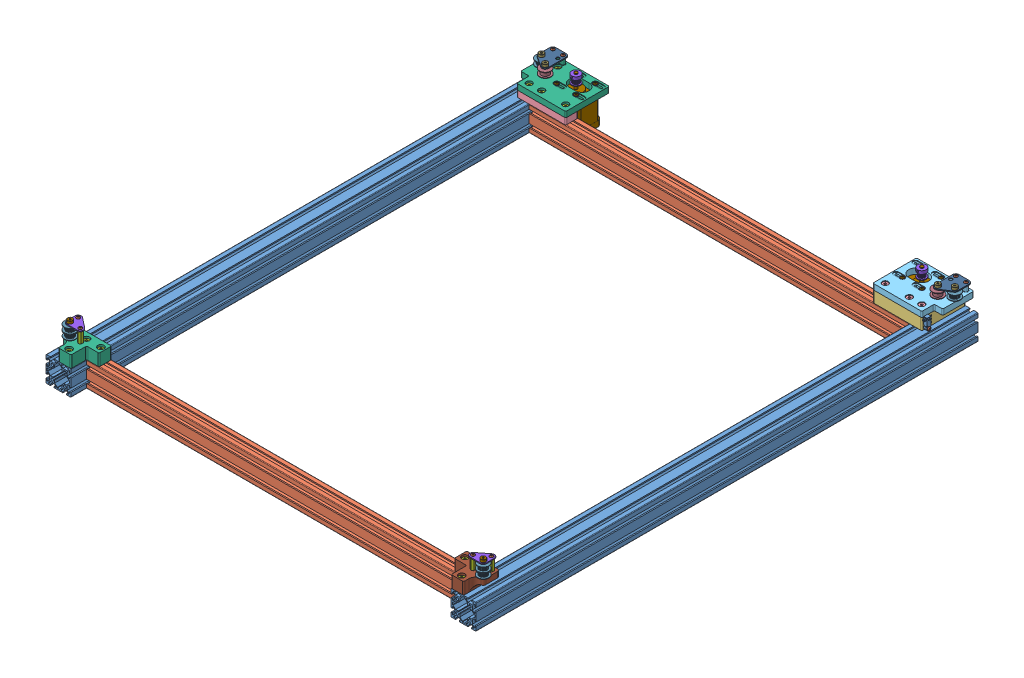
SolidWorks assembly BigCoreXYFrame, configuration Default. Lengths in mm.
Overall size (689 83.14 804).
125 component instances, 29 part files, 15 mates.
Components (placement in the parent):
- BaseModel20200203215901-4: BaseModel20200203215901 [Default] at (0 0.4187 49.2065) x (0 0 -1) z (0 -1 0) size (804 40 40)
- BaseModel20200203215901-3: BaseModel20200203215901 [Default] at (649 0.4187 49.2065) x (0 0 -1) z (0 -1 0) size (804 40 40)
- MISUMI_NFS5-2040-609.0-1: MISUMI_NFS5-2040-609.0 [Default] at (20 0.4187 -694.7935) size (609 40 20)
- MISUMI_NFS5-2040-609.0-2: MISUMI_NFS5-2040-609.0 [Default] at (20 0.4187 14.2065) size (609 40 20)
- left_motor_plate_assembly-1: left_motor_plate_assembly [Default] at (74.929 -353.5918 -700.1092) size (94 73.14 70)
  - m5_locking_t_nut_20x20_generic-1: m5_locking_t_nut_20x20_generic [Default] at (-9.429 368.8105 5.3157) x (0 0 -1) z (1 0 0) size (10 4.5 6)
  - m5_locking_t_nut_20x20_generic-2: m5_locking_t_nut_20x20_generic [Default] at (-64.929 368.8105 2.3157) size (10 4.5 6)
  - m5_locking_t_nut_20x20_generic-3: m5_locking_t_nut_20x20_generic [Default] at (-64.929 368.8105 -43.6843) size (10 4.5 6)
  - m5_locking_t_nut_20x20_generic-4: m5_locking_t_nut_20x20_generic [Default] at (-47.929 368.8105 5.3157) x (0 0 -1) z (1 0 0) size (10 4.5 6)
  - short_motor_corner_plate_spacer_with_insert-1: short_motor_corner_plate_spacer_with_insert [Default] at (-74.929 374.0105 -59.4612) x (0 0 -1) z (0 -1 0) size (70 78.5 10)
    - motor_corner_bracket_spacer_Left Motor Corner Bracket Spacer-1: motor_corner_bracket_spacer_Left Motor Corner Bracket Spacer [Default] at (-74.7769 0 0) x (0 1 0) z (-1 0 0) size (78.5 10 70)
    - m4_heat_set_insert_long_94180A353_94180A353-1: m4_heat_set_insert_long_94180A353_94180A353 [Default] at (-27.2769 20 -5.5) x (0.97178 0 0.235889) z (-0.235889 0 0.97178) size (6.35 8 6.35)
  - left_motor_plate_with_inserts-1: left_motor_plate_with_inserts [Default] at origin size (92 19 70)
    - m4_heat_set_insert_long_94180A353_94180A353-1: m4_heat_set_insert_long_94180A353_94180A353 [Default] at (-81.429 393.0105 -31.0093) size (6.35 8 6.35)
    - motor_corner_bracket_Left Motor Corner Bracket-1: motor_corner_bracket_Left Motor Corner Bracket [Default] at (-74.929 384.0105 15.3157) size (92 19 70)
    - m4_heat_set_insert_long_94180A353_94180A353-2: m4_heat_set_insert_long_94180A353_94180A353 [Default] at (-64.929 393.0105 -20.3843) size (6.35 8 6.35)
  - m5_low_profile_screw_template_M5 x 20-1: m5_low_profile_screw_template_M5 x 20 [Default] at (-44.929 368.8105 5.3157) x (0 -1 0) z (-0.441015 0 -0.8975) size (21.62 9 9)
  - m5_low_profile_screw_template_M5 x 20-2: m5_low_profile_screw_template_M5 x 20 [Default] at (-64.929 368.8105 5.3157) x (0 -1 0) z (0.595693 0 0.803212) size (21.62 9 9)
  - m5_low_profile_screw_template_M5 x 20-3: m5_low_profile_screw_template_M5 x 20 [Default] at (-64.929 368.8105 -40.6843) x (0 -1 0) z (0.317209 0 -0.948356) size (21.62 9 9)
  - m5_low_profile_screw_template_M5 x 20-4: m5_low_profile_screw_template_M5 x 20 [Default] at (-6.429 368.8105 5.3157) x (0 -1 0) z (-0.441015 0 -0.8975) size (21.62 9 9)
  - xy_drive_stepper-1: xy_drive_stepper [Default] at origin size (42.42 72 42.42)
    - drive_pulley_16t_gt2_6mm_belt-1: drive_pulley_16t_gt2_6mm_belt [Default] at (-27.429 406.7309 -32.1843) x (-0.044306 0 -0.999018) z (-0.999018 0 0.044306) size (13.8 13.5 13.8)
    - 17HM19-2004S-1: 17HM19-2004S [Default] at (-27.429 384.0105 -32.1843) x (-1 0 0) z (0 1 0) size (42.42 42.42 72)
  - motor_plate_reinforcement-1: motor_plate_reinforcement [Default] at (-86.429 403.0105 -54.0093) size (26.5 1.57 38.62)
  - m3_6mm_buttonhead_screw_92095A179_92095A179-1: m3_6mm_buttonhead_screw_92095A179_92095A179 [Default] at (-81.429 406.2305 -49.0093) x (1 0 0) z (0 1 0) size (5.74 5.77 8.05)
  - m3_6mm_buttonhead_screw_92095A179_92095A179-2: m3_6mm_buttonhead_screw_92095A179_92095A179 [Default] at (-64.929 406.2305 -49.0093) x (1 0 0) z (0 1 0) size (5.74 5.77 8.05)
  - m4_shoulder_screw_5mm_d_12mm_l_90278A371_90278A371-1: m4_shoulder_screw_5mm_d_12mm_l_90278A371_90278A371 [Default] at (-64.929 409.0105 -20.3843) x (1 0 0) z (0 1 0) size (8 8 21.19)
  - m4_shoulder_screw_5mm_d_12mm_l_90278A371_90278A371-2: m4_shoulder_screw_5mm_d_12mm_l_90278A371_90278A371 [Default] at (-81.429 409.0105 -31.0093) x (1 0 0) z (0 1 0) size (8 8 21.19)
  - 20t_toothless_idler_5mm_bore-1: 20t_toothless_idler_5mm_bore [Default] at (-64.929 393.2105 -20.3843) x (0.999784 0 0.020777) z (-0.020777 0 0.999784) size (18 8.5 18)
  - 20t_idler_5mm_bore-1: 20t_idler_5mm_bore [Default] at (-81.429 393.2105 -31.0093) size (18 8.5 18)
  - m5_shim_0.2mm_thick_98089A246_98089A246-1: m5_shim_0.2mm_thick_98089A246_98089A246 [Default] at (-64.929 393.2105 -20.3843) x (-0.674811 0 -0.73799) z (-0.73799 0 0.674811) size (10 0.2 10)
  - m5_shim_0.2mm_thick_98089A246_98089A246-2: m5_shim_0.2mm_thick_98089A246_98089A246 [Default] at (-81.429 393.2105 -31.0093) x (-0.777784 0 -0.628532) z (-0.628532 0 0.777784) size (10 0.2 10)
  - m4_set_screw_25mm_92605A124_92605A124-1: m4_set_screw_25mm_92605A124_92605A124 [Default] at (-64.429 379.5105 -32.1843) x (0 0.718145 0.695894) z (-1 0 0) size (4.05 4.11 25.09)
  - m3_stainless_steel_washer_90965A130_90965A130-1: m3_stainless_steel_washer_90965A130_90965A130 [Default] at (-42.929 391.8105 -47.6843) x (1 0 0) z (0 1 0) size (7 7 0.6)
  - m3_12mm_buttohead_screw_92095A183_92095A183-1: m3_12mm_buttohead_screw_92095A183_92095A183 [Default] at (-42.929 394.0605 -47.6843) x (1 0 0) z (0 1 0) size (5.74 5.77 14.06)
  - m3_12mm_buttohead_screw_92095A183_92095A183-2: m3_12mm_buttohead_screw_92095A183_92095A183 [Default] at (-11.929 394.0605 -47.6843) x (0 0 1) z (0 1 0) size (5.74 5.77 14.06)
  - m3_12mm_buttohead_screw_92095A183_92095A183-3: m3_12mm_buttohead_screw_92095A183_92095A183 [Default] at (-11.929 394.0605 -16.6843) x (-1 0 0) z (0 1 0) size (5.74 5.77 14.06)
  - m3_12mm_buttohead_screw_92095A183_92095A183-4: m3_12mm_buttohead_screw_92095A183_92095A183 [Default] at (-42.929 394.0605 -16.6843) x (0 0 -1) z (0 1 0) size (5.74 5.77 14.06)
  - m3_stainless_steel_washer_90965A130_90965A130-2: m3_stainless_steel_washer_90965A130_90965A130 [Default] at (-11.929 391.8105 -47.6843) x (0 0 1) z (0 1 0) size (7 7 0.6)
  - m3_stainless_steel_washer_90965A130_90965A130-3: m3_stainless_steel_washer_90965A130_90965A130 [Default] at (-11.929 391.8105 -16.6843) x (-1 0 0) z (0 1 0) size (7 7 0.6)
  - m3_stainless_steel_washer_90965A130_90965A130-4: m3_stainless_steel_washer_90965A130_90965A130 [Default] at (-42.929 391.8105 -16.6843) x (0 0 -1) z (0 1 0) size (7 7 0.6)
- right_motor_plate_assembly-1: right_motor_plate_assembly [Default] at (294.929 -353.5918 -700.1092) size (94 73.14 71.2)
  - tall_motor_corner_plate_spacer_assembly-1: tall_motor_corner_plate_spacer_assembly [Default] at origin size (85.83 18.61 71.2)
    - D2HW_C201H-1: D2HW_C201H [Default] at (354.071 389.8605 9.3157) x (0 -1 0) z (-1 0 0) size (18.5 14.2 8.3)
    - m3_8mm_buttonhead_screw_92095A181_92095A181-1: m3_8mm_buttonhead_screw_92095A181_92095A181 [Default] at (361.021 376.8605 9.3157) x (0 -0.028648 -0.99959) z (1 0 0) size (5.74 5.77 10.05)
    - tall_motor_corner_plate_spacer_with_insert-1: tall_motor_corner_plate_spacer_with_insert [Default] at (354.071 392.0105 -198.139) x (0 0 -1) z (0 1 0) size (70 78.5 18)
      - motor_corner_bracket_spacer_Right Motor Corner Bracket Spacer-1: motor_corner_bracket_spacer_Right Motor Corner Bracket Spacer [Default] at (-213.4548 157 -10) x (0 -1 0) z (-1 0 0) size (78.5 18 70)
      - m4_heat_set_insert_long_94180A353_94180A353-1: m4_heat_set_insert_long_94180A353_94180A353 [Default] at (-165.9548 20 -4.5) x (0.989318 0 -0.145772) z (0.145772 0 0.989318) size (6.35 8 6.35)
    - m4_set_screw_25mm_92605A124_92605A124-1: m4_set_screw_25mm_92605A124_92605A124 [Default] at (345.571 387.5105 -32.1843) x (0 -0.291374 0.956609) z (1 0 0) size (4.05 4.11 25.09)
  - m5_low_profile_screw_template_M5 x 30-1: m5_low_profile_screw_template_M5 x 30 [Default] at (344.071 368.8105 5.3157) x (0 -1 0) z (-0.571239 0 -0.820784) size (31.62 9 9)
  - m5_low_profile_screw_template_M5 x 30-2: m5_low_profile_screw_template_M5 x 30 [Default] at (324.071 368.8105 5.3157) x (0 -1 0) z (-0.571239 0 -0.820784) size (31.62 9 9)
  - m5_low_profile_screw_template_M5 x 30-3: m5_low_profile_screw_template_M5 x 30 [Default] at (285.571 368.8105 5.3157) x (0 -1 0) z (-0.917889 0 0.396837) size (31.62 9 9)
  - motor_plate_reinforcement-1: motor_plate_reinforcement [Default] at (365.699 412.5805 -53.9811) x (-0.999984 0 -0.005572) z (-0.005572 0 0.999984) size (26.5 1.57 38.62)
  - m3_6mm_buttonhead_screw_92095A179_92095A179-1: m3_6mm_buttonhead_screw_92095A179_92095A179 [Default] at (344.1715 414.2305 -49.1009) x (1 0 0) z (0 1 0) size (5.74 5.77 8.05)
  - m3_6mm_buttonhead_screw_92095A179_92095A179-2: m3_6mm_buttonhead_screw_92095A179_92095A179 [Default] at (360.6712 414.2305 -49.009) x (1 0 0) z (0 1 0) size (5.74 5.77 8.05)
  - m4_shoulder_screw_5mm_d_12mm_l_90278A371_90278A371-1: m4_shoulder_screw_5mm_d_12mm_l_90278A371_90278A371 [Default] at (360.571 417.0105 -31.0093) x (1 0 0) z (0 1 0) size (8 8 21.19)
  - m4_shoulder_screw_5mm_d_12mm_l_90278A371_90278A371-2: m4_shoulder_screw_5mm_d_12mm_l_90278A371_90278A371 [Default] at (344.071 417.0105 -20.3843) x (1 0 0) z (0 1 0) size (8 8 21.19)
  - m3_12mm_buttohead_screw_92095A183_92095A183-1: m3_12mm_buttohead_screw_92095A183_92095A183 [Default] at (291.071 402.0605 -47.6843) x (1 0 0) z (0 1 0) size (5.74 5.77 14.06)
  - m3_stainless_steel_washer_90965A130_90965A130-1: m3_stainless_steel_washer_90965A130_90965A130 [Default] at (291.071 399.8105 -47.6843) x (0.988493 0 -0.151268) z (0 1 0) size (7 7 0.6)
  - xy_drive_stepper_2-1: xy_drive_stepper_2 [Default] at (334 8 0) size (42.42 72 42.42)
    - drive_pulley_16t_gt2_6mm_belt-1: drive_pulley_16t_gt2_6mm_belt [Default] at (-27.429 406.7309 -32.1843) x (-0.044306 0 -0.999018) z (-0.999018 0 0.044306) size (13.8 13.5 13.8)
    - 17HM19-2004S-1: 17HM19-2004S [Default] at (-27.429 384.0105 -32.1843) x (-1 0 0) z (0 1 0) size (42.42 42.42 72)
  - m5_locking_t_nut_20x20_generic-1: m5_locking_t_nut_20x20_generic [Default] at (344.071 368.8105 -37.6843) x (-1 0 0) z (0 0 -1) size (10 4.5 6)
  - m5_locking_t_nut_20x20_generic-2: m5_locking_t_nut_20x20_generic [Default] at (344.071 368.8105 8.3157) x (-1 0 0) z (0 0 -1) size (10 4.5 6)
  - m5_locking_t_nut_20x20_generic-3: m5_locking_t_nut_20x20_generic [Default] at (288.571 368.8105 5.3157) x (0 0 1) z (-1 0 0) size (10 4.5 6)
  - m5_locking_t_nut_20x20_generic-4: m5_locking_t_nut_20x20_generic [Default] at (327.071 368.8105 5.3157) x (0 0 1) z (-1 0 0) size (10 4.5 6)
  - m5_shim_0.2mm_thick_98089A246_98089A246-1: m5_shim_0.2mm_thick_98089A246_98089A246 [Default] at (360.571 401.2105 -31.0093) x (0.674811 0 0.73799) z (0.73799 0 -0.674811) size (10 0.2 10)
  - m5_shim_0.2mm_thick_98089A246_98089A246-2: m5_shim_0.2mm_thick_98089A246_98089A246 [Default] at (344.071 401.0105 -20.3843) x (-0.968571 0 0.248739) z (-0.248739 0 -0.968571) size (10 0.2 10)
  - right_motor_plate_with_inserts-1: right_motor_plate_with_inserts [Default] at origin size (92 19 70)
    - motor_corner_bracket_Right Motor Corner Bracket-1: motor_corner_bracket_Right Motor Corner Bracket [Default] at (197.071 392.0105 15.3157) size (92 19 70)
    - m4_heat_set_insert_long_94180A353_94180A353-1: m4_heat_set_insert_long_94180A353_94180A353 [Default] at (360.571 401.0105 -31.0093) size (6.35 8 6.35)
    - m4_heat_set_insert_long_94180A353_94180A353-2: m4_heat_set_insert_long_94180A353_94180A353 [Default] at (344.071 401.0105 -20.3843) size (6.35 8 6.35)
  - m5_low_profile_screw_template_M5 x 30-4: m5_low_profile_screw_template_M5 x 30 [Default] at (344.071 368.8105 -40.6843) x (0 -1 0) z (-0.6826 0 -0.730792) size (31.62 9 9)
  - 20t_toothless_idler_5mm_bore-1: 20t_toothless_idler_5mm_bore [Default] at (344.071 401.2105 -20.3843) x (0.998302 0 -0.058244) z (0.058244 0 0.998302) size (18 8.5 18)
  - 20t_idler_5mm_bore-1: 20t_idler_5mm_bore [Default] at (360.571 401.2105 -31.0093) size (18 8.5 18)
  - m3_stainless_steel_washer_90965A130_90965A130-2: m3_stainless_steel_washer_90965A130_90965A130 [Default] at (322.071 399.8105 -47.6843) x (0.151268 0 0.988493) z (0 1 0) size (7 7 0.6)
  - m3_stainless_steel_washer_90965A130_90965A130-3: m3_stainless_steel_washer_90965A130_90965A130 [Default] at (322.071 399.8105 -16.6843) x (-0.988493 0 0.151268) z (0 1 0) size (7 7 0.6)
  - m3_stainless_steel_washer_90965A130_90965A130-4: m3_stainless_steel_washer_90965A130_90965A130 [Default] at (291.071 399.8105 -16.6843) x (-0.151268 0 -0.988493) z (0 1 0) size (7 7 0.6)
  - m3_12mm_buttohead_screw_92095A183_92095A183-2: m3_12mm_buttohead_screw_92095A183_92095A183 [Default] at (322.071 402.0605 -47.6843) x (0 0 1) z (0 1 0) size (5.74 5.77 14.06)
  - m3_12mm_buttohead_screw_92095A183_92095A183-3: m3_12mm_buttohead_screw_92095A183_92095A183 [Default] at (322.071 402.0605 -16.6843) x (-1 0 0) z (0 1 0) size (5.74 5.77 14.06)
  - m3_12mm_buttohead_screw_92095A183_92095A183-4: m3_12mm_buttohead_screw_92095A183_92095A183 [Default] at (291.071 402.0605 -16.6843) x (0 0 -1) z (0 1 0) size (5.74 5.77 14.06)
- left_corner_pulley_assembly-1: left_corner_pulley_assembly [Default] at (74.929 -353.5918 -479.1092) size (55.52 48.14 55)
  - left_corner_plate_with_insert-1: left_corner_plate_with_insert [Default] at origin size (53 19.06 55)
    - double_pulley_corner_bracket_Left Double Pulley Corner Bracket-1: double_pulley_corner_bracket_Left Double Pulley Corner Bracket [Default] at (-74.929 374.0105 528.3157) size (53 19.01 55)
    - m4_heat_set_insert_long_94180A353_94180A353-1: m4_heat_set_insert_long_94180A353_94180A353 [Default] at (-81.429 393.0105 503.3157) size (6.35 8 6.35)
  - m3_18mm_hex_standoff_6mm_wide_95947A525_95947A525-1: m3_18mm_hex_standoff_6mm_wide_95947A525_95947A525 [Default] at (-81.429 402.0105 490.3157) x (1 0 0) z (0 1 0) size (6 6.93 18)
  - m3_18mm_hex_standoff_6mm_wide_95947A525_95947A525-2: m3_18mm_hex_standoff_6mm_wide_95947A525_95947A525 [Default] at (-64.929 402.0105 503.3157) x (1 0 0) z (0 1 0) size (6 6.93 18)
  - back_pulley_reinforcement_plate-1: back_pulley_reinforcement_plate [Default] at (-81.429 411.0105 503.3157) size (26.5 1.57 23)
  - m4_shoulder_screw_5mm_d_20mm_l_90278A374_90278A374-1: m4_shoulder_screw_5mm_d_20mm_l_90278A374_90278A374 [Default] at (-81.429 417.0105 503.3157) x (0.147585 0 0.989049) z (0 1 0) size (8 8 29.19)
  - m3_6mm_buttonhead_screw_92095A179_92095A179-1: m3_6mm_buttonhead_screw_92095A179_92095A179 [Default] at (-81.429 414.2305 490.3157) x (1 0 0) z (0 1 0) size (5.74 5.77 8.05)
  - m3_6mm_buttonhead_screw_92095A179_92095A179-2: m3_6mm_buttonhead_screw_92095A179_92095A179 [Default] at (-64.929 414.2305 503.3157) x (1 0 0) z (0 1 0) size (5.74 5.77 8.05)
  - m3_10mm_buttonhead_screw_92095A182_92095A182-1: m3_10mm_buttonhead_screw_92095A182_92095A182 [Default] at (-81.429 385.3605 490.3157) x (1 0 0) z (0 -1 0) size (5.74 5.77 12.06)
  - m3_10mm_buttonhead_screw_92095A182_92095A182-2: m3_10mm_buttonhead_screw_92095A182_92095A182 [Default] at (-64.929 385.3605 503.3157) x (1 0 0) z (0 -1 0) size (5.74 5.77 12.06)
  - m5_low_profile_screw_template_M5 x 20-1: m5_low_profile_screw_template_M5 x 20 [Default] at (-64.929 369.0105 521.3157) x (0 -1 0) z (-0.953053 0 -0.302804) size (21.62 9 9)
  - m5_low_profile_screw_template_M5 x 20-2: m5_low_profile_screw_template_M5 x 20 [Default] at (-64.929 369.0105 493.3157) x (0 -1 0) z (0.203237 0 -0.979129) size (21.62 9 9)
  - m5_low_profile_screw_template_M5 x 20-3: m5_low_profile_screw_template_M5 x 20 [Default] at (-41.929 369.0105 493.3157) x (0 -1 0) z (0.194951 0 -0.980813) size (21.62 9 9)
  - m5_shim_0.2mm_thick_98089A246_98089A246-1: m5_shim_0.2mm_thick_98089A246_98089A246 [Default] at (-81.429 393.0105 503.3157) size (10 0.2 10)
  - 20t_idler_5mm_bore-1: 20t_idler_5mm_bore [Default] at (-81.429 393.2105 503.3157) x (0.999997 0 0.002498) z (-0.002498 0 0.999997) size (18 8.5 18)
  - m5_shim_0.2mm_thick_98089A246_98089A246-2: m5_shim_0.2mm_thick_98089A246_98089A246 [Default] at (-81.429 401.7105 503.3157) size (10 0.2 10)
  - 20t_idler_5mm_bore-2: 20t_idler_5mm_bore [Default] at (-81.429 401.9105 503.3157) x (0.999997 0 0.002498) z (-0.002498 0 0.999997) size (18 8.5 18)
  - m5_locking_t_nut_20x20_generic-1: m5_locking_t_nut_20x20_generic [Default] at (-64.929 369.0105 518.3157) size (10 4.5 6)
  - m5_locking_t_nut_20x20_generic-2: m5_locking_t_nut_20x20_generic [Default] at (-64.929 369.0105 490.3157) size (10 4.5 6)
  - m5_locking_t_nut_20x20_generic-3: m5_locking_t_nut_20x20_generic [Default] at (-44.929 369.0105 493.3157) x (0 0 -1) z (1 0 0) size (10 4.5 6)
- right_corner_pulley_assembly-1: right_corner_pulley_assembly [Default] at (294.929 -353.5918 -479.1092) size (58.84 48.14 55)
  - right_corner_plate_with_insert-1: right_corner_plate_with_insert [Default] at (10 0 0) size (53 19.05 55)
    - double_pulley_corner_bracket_Right Double Pulley Corner Bracket-1: double_pulley_corner_bracket_Right Double Pulley Corner Bracket [Default] at (264.071 374.0105 528.3157) size (53 19 55)
    - m4_heat_set_insert_long_94180A353_94180A353-1: m4_heat_set_insert_long_94180A353_94180A353 [Default] at (350.571 393.0105 503.3157) size (6.35 8 6.35)
  - m3_18mm_hex_standoff_6mm_wide_95947A525_95947A525-1: m3_18mm_hex_standoff_6mm_wide_95947A525_95947A525 [Default] at (360.571 402.0105 490.3157) x (1 0 0) z (0 1 0) size (6 6.93 18)
  - m3_18mm_hex_standoff_6mm_wide_95947A525_95947A525-2: m3_18mm_hex_standoff_6mm_wide_95947A525_95947A525 [Default] at (344.071 402.0105 503.3157) x (1 0 0) z (0 1 0) size (6 6.93 18)
  - back_pulley_reinforcement_plate-1: back_pulley_reinforcement_plate [Default] at (360.571 412.5805 503.3157) x (-1 0 0) z (0 0 1) size (26.5 1.57 23)
  - m4_shoulder_screw_5mm_d_20mm_l_90278A374_90278A374-1: m4_shoulder_screw_5mm_d_20mm_l_90278A374_90278A374 [Default] at (360.571 417.0105 503.3157) x (0.147585 0 0.989049) z (0 1 0) size (8 8 29.19)
  - m3_10mm_buttonhead_screw_92095A182_92095A182-1: m3_10mm_buttonhead_screw_92095A182_92095A182 [Default] at (344.071 385.3605 503.3157) x (1 0 0) z (0 -1 0) size (5.74 5.77 12.06)
  - m3_10mm_buttonhead_screw_92095A182_92095A182-2: m3_10mm_buttonhead_screw_92095A182_92095A182 [Default] at (360.571 385.3605 490.3157) x (1 0 0) z (0 -1 0) size (5.74 5.77 12.06)
  - m3_6mm_buttonhead_screw_92095A179_92095A179-1: m3_6mm_buttonhead_screw_92095A179_92095A179 [Default] at (360.571 414.2305 490.3157) x (1 0 0) z (0 1 0) size (5.74 5.77 8.05)
  - m3_6mm_buttonhead_screw_92095A179_92095A179-2: m3_6mm_buttonhead_screw_92095A179_92095A179 [Default] at (344.071 414.2305 503.3157) x (1 0 0) z (0 1 0) size (5.74 5.77 8.05)
  - m5_low_profile_screw_template_M5 x 20-1: m5_low_profile_screw_template_M5 x 20 [Default] at (321.071 369.0105 493.3157) x (0 -1 0) z (0.874861 0 0.484375) size (21.62 9 9)
  - m5_low_profile_screw_template_M5 x 20-2: m5_low_profile_screw_template_M5 x 20 [Default] at (344.071 369.0105 493.3157) x (0 -1 0) z (0.874267 0 0.485445) size (21.62 9 9)
  - m5_low_profile_screw_template_M5 x 20-3: m5_low_profile_screw_template_M5 x 20 [Default] at (344.071 369.0105 521.3157) x (0 -1 0) z (-0.681019 0 0.732266) size (21.62 9 9)
  - 20t_idler_5mm_bore-1: 20t_idler_5mm_bore [Default] at (360.571 393.2105 503.3157) x (0.999997 0 0.002498) z (-0.002498 0 0.999997) size (18 8.5 18)
  - 20t_idler_5mm_bore-2: 20t_idler_5mm_bore [Default] at (360.571 401.9105 503.3157) x (0.85881 0 0.512295) z (-0.512295 0 0.85881) size (18 8.5 18)
  - m5_locking_t_nut_20x20_generic-1: m5_locking_t_nut_20x20_generic [Default] at (344.071 369.0105 518.3157) size (10 4.5 6)
  - m5_locking_t_nut_20x20_generic-2: m5_locking_t_nut_20x20_generic [Default] at (344.071 369.0105 490.3157) size (10 4.5 6)
  - m5_locking_t_nut_20x20_generic-3: m5_locking_t_nut_20x20_generic [Default] at (318.071 369.0105 493.3157) x (0 0 -1) z (1 0 0) size (10 4.5 6)
  - m5_shim_0.2mm_thick_98089A246_98089A246-1: m5_shim_0.2mm_thick_98089A246_98089A246 [Default] at (360.571 393.0105 503.3157) x (0.760721 0 -0.649079) z (0.649079 0 0.760721) size (10 0.2 10)
  - m5_shim_0.2mm_thick_98089A246_98089A246-2: m5_shim_0.2mm_thick_98089A246_98089A246 [Default] at (360.571 401.7105 503.3157) x (0.760721 0 -0.649079) z (0.649079 0 0.760721) size (10 0.2 10)
Mates (geometry in assembly coordinates):
- Coincident29: coincident anti-aligned: plane of BaseModel20200203215901-3 through (629 -6.5813 -754.7935) normal (-1 0 0); plane of MISUMI_NFS5-2040-609.0-1 through (629 -18.5813 -685.7935) normal (1 0 0)
- Coincident30: coincident anti-aligned: plane of BaseModel20200203215901-4 through (20 7.4187 -754.7935) normal (1 0 0); plane of MISUMI_NFS5-2040-609.0-1 through (20 -18.5813 -685.7935) normal (-1 0 0)
- Coincident31: coincident aligned: plane of BaseModel20200203215901-3 through (629 -6.5813 -754.7935) normal (-1 0 0); plane of right_motor_plate_assembly-1/tall_motor_corner_plate_spacer_assembly-1/tall_motor_corner_plate_spacer_with_insert-1/motor_corner_bracket_spacer_Right Motor Corner Bracket Spacer-1 through (629 38.4187 -704.7935) normal (-1 0 0)
- Coincident32: coincident anti-aligned: plane of BaseModel20200203215901-3 through (629 -6.5813 -754.7935) normal (-1 0 0); plane of MISUMI_NFS5-2040-609.0-2 through (629 -18.5813 23.2065) normal (1 0 0)
- Distance7: distance = 25 mm aligned: plane of BaseModel20200203215901-3 through (668 -18.5813 49.2065) normal (0 0 1); plane of MISUMI_NFS5-2040-609.0-2 through (629 7.4187 24.2065) normal (0 0 1)
- Coincident34: coincident aligned: plane of BaseModel20200203215901-3 through (629 -6.5813 -754.7935) normal (-1 0 0); plane of right_corner_pulley_assembly-1/right_corner_plate_with_insert-1/double_pulley_corner_bracket_Right Double Pulley Corner Bracket-1 through (629 30.4187 24.2065) normal (-1 0 0)
- Coincident35: coincident aligned: plane of BaseModel20200203215901-4 through (20 7.4187 -754.7935) normal (1 0 0); plane of left_corner_pulley_assembly-1/left_corner_plate_with_insert-1/double_pulley_corner_bracket_Left Double Pulley Corner Bracket-1 through (20 30.4187 24.2065) normal (1 0 0)
- Coincident36: coincident aligned: plane of BaseModel20200203215901-4 through (19 -18.5813 49.2065) normal (0 0 1); plane of left_corner_pulley_assembly-1/left_corner_plate_with_insert-1/double_pulley_corner_bracket_Left Double Pulley Corner Bracket-1 through (20 30.4187 49.2065) normal (0 0 1)
- Coincident37: coincident aligned: plane of BaseModel20200203215901-4 through (13 20.4187 -754.7935) normal (0 1 0); plane of MISUMI_NFS5-2040-609.0-2 through (629 20.4187 5.2065) normal (0 1 0)
- Coincident38: coincident aligned: plane of BaseModel20200203215901-4 through (19 -18.5813 -754.7935) normal (0 0 -1); plane of left_motor_plate_assembly-1/short_motor_corner_plate_spacer_with_insert-1/motor_corner_bracket_spacer_Left Motor Corner Bracket Spacer-1 through (20 30.4187 -754.7935) normal (0 0 -1)
- Coincident39: coincident aligned: plane of BaseModel20200203215901-4 through (20 19.4187 -754.7935) normal (1 0 0); plane of left_motor_plate_assembly-1/short_motor_corner_plate_spacer_with_insert-1/motor_corner_bracket_spacer_Left Motor Corner Bracket Spacer-1 through (20 30.4187 -704.7935) normal (1 0 0)
- Distance8: distance = 50 mm aligned: plane of BaseModel20200203215901-3 through (668 -18.5813 -754.7935) normal (0 0 -1); plane of MISUMI_NFS5-2040-609.0-1 through (629 -6.5813 -704.7935) normal (0 0 -1)
- Coincident42: coincident aligned: plane of BaseModel20200203215901-3 through (668 -18.5813 -754.7935) normal (0 0 -1); plane of right_motor_plate_assembly-1/tall_motor_corner_plate_spacer_assembly-1/tall_motor_corner_plate_spacer_with_insert-1/motor_corner_bracket_spacer_Right Motor Corner Bracket Spacer-1 through (629 38.4187 -754.7935) normal (0 0 -1)
- Coincident43: coincident anti-aligned: plane of BaseModel20200203215901-3 through (642 20.4187 -754.7935) normal (0 1 0); plane of right_motor_plate_assembly-1/tall_motor_corner_plate_spacer_assembly-1/tall_motor_corner_plate_spacer_with_insert-1/motor_corner_bracket_spacer_Right Motor Corner Bracket Spacer-1 through (647 20.4187 -752.7935) normal (0 -1 0)
- Distance9: distance = 50 mm aligned: plane of MISUMI_NFS5-2040-609.0-1 through (629 -6.5813 -704.7935) normal (0 0 -1); plane of BaseModel20200203215901-4 through (19 -18.5813 -754.7935) normal (0 0 -1)
